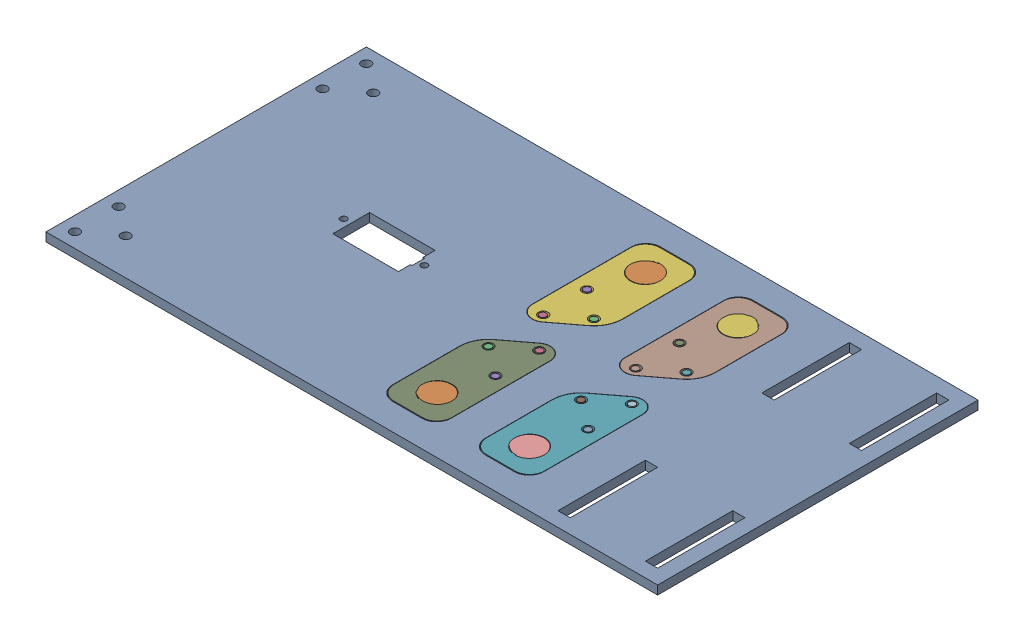
SolidWorks assembly frame, configuration Default. Lengths in mm.
Overall size (210 3 110).
5 component instances, 2 part files, 13 mates.
Components (placement in the parent):
- main_frame-1: main_frame [Default] at (20.9082 -26.0171 5.6236) size (210 3 110)
- hinge-3: hinge [Default] at (30.8724 -26.0171 -7.5897) size (19.8 3 43.07)
- hinge-4: hinge [Default] at (62.6724 -26.0171 18.7014) x (-1 0 0) z (0 0 -1) size (19.8 3 43.07)
- hinge-6: hinge [Default] at (62.6724 -26.0171 -7.5897) size (19.8 3 43.07)
- hinge-7: hinge [Default] at (30.8724 -26.0171 18.7014) x (-1 0 0) z (0 0 -1) size (19.8 3 43.07)
Mates (geometry in assembly coordinates):
- Coincident13: coincident aligned: plane of fix-3 through (25.3498 -23.0171 -1.3975) normal (0 1 0); plane of fix-7 through (36.395 -23.0171 12.5092) normal (0 1 0)
- Coincident14: coincident aligned: plane of fix-3 through (40.7724 -23.0171 -35.0897) normal (1 0 0); plane of fix-7 through (40.7724 -23.0171 46.2014) normal (1 0 0)
- Coincident15: coincident aligned: plane of fix-4 through (68.195 -23.0171 12.5092) normal (0 1 0); plane of fix-6 through (57.1498 -23.0171 -1.3975) normal (0 1 0)
- Coincident16: coincident aligned: plane of fix-4 through (72.5724 -23.0171 46.2014) normal (1 0 0); plane of fix-6 through (72.5724 -23.0171 -35.0897) normal (1 0 0)
- Coincident17: coincident aligned: plane of fix-3 through (25.3498 -23.0171 -1.3975) normal (0 1 0); plane of fix-6 through (57.1498 -23.0171 -1.3975) normal (0 1 0)
- Parallel3: parallel aligned: plane of mica-1 through (20.9082 -23.0171 5.6236) normal (0 1 0); plane of fix-3 through (25.3498 -23.0171 -1.3975) normal (0 1 0)
- Parallel4: parallel anti-aligned: plane of fix-3 through (40.7724 -23.0171 -35.0897) normal (1 0 0); plane of fix-6 through (52.7724 -23.0171 -35.0897) normal (-1 0 0)
- Coincident20: coincident aligned: plane of fix-3 through (35.7724 -23.0171 -40.0897) normal (0 0 -1); plane of fix-6 through (67.5724 -23.0171 -40.0897) normal (0 0 -1)
- Coincident21: coincident aligned: plane of fix-4 through (57.7724 -23.0171 51.2014) normal (0 0 1); plane of fix-7 through (25.9724 -23.0171 51.2014) normal (0 0 1)
- Coincident22: coincident aligned: plane of mica-1 through (20.9082 -23.0171 5.6236) normal (0 1 0); plane of fix-4 through (68.195 -23.0171 12.5092) normal (0 1 0)
- Parallel5: parallel aligned: plane of mica-1 through (20.9082 -23.0171 60.6236) normal (0 0 1); plane of fix-4 through (57.7724 -23.0171 51.2014) normal (0 0 1)
- Distance1: distance = 12 mm: line of fix-7 through (40.7724 -23.0171 46.2014) axis (0 0 -1); line of fix-4 through (52.7724 -23.0171 23.6712) axis (0 0 1)
- Distance2: distance = 9 mm: line of fix-6 through (59.7664 -23.0171 2.1118) axis (0.797092 0 -0.603858); line of fix-4 through (65.5784 -23.0171 8.9998) axis (-0.797092 0 0.603858)
